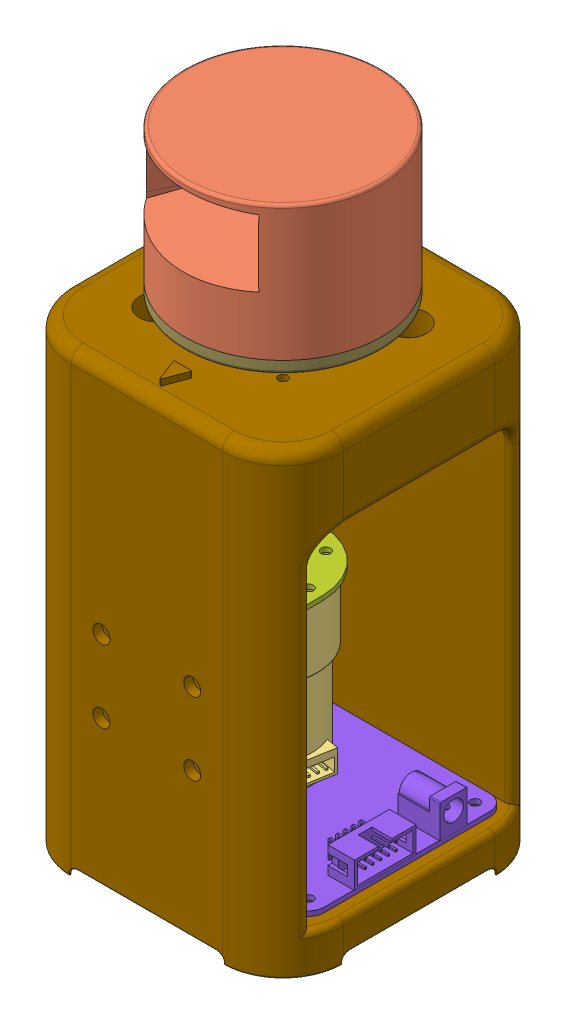
SolidWorks assembly 动画制作, configuration 默认. Lengths in mm.
Overall size (139.14 209.97 139.14).
12 component instances, 12 part files, 31 mates.
Components (placement in the parent):
- TFminiPlus激光测距模组-1: TFminiPlus激光测距模组 [默认] at (220.1693 461.3412 -162.2181) x (0.983804 0 0.179245) z (0 -1 0) size (35 21.2 40.5)
- 转子盖-1: 转子盖 [Default] at (216.4052 396.0912 -141.5582) x (-0.983804 0 -0.179245) z (0 1 0) size (65 68.94 49.1)
- MG513电机-光电编码器-1: MG513电机-光电编码器 [Default] at (216.4052 352.7568 -134.5582) x (1 0 0) z (0 0 -1) size (37.69 78.06 36.8)
- 传动轴-1: 传动轴 [Default] at (216.4052 354.2568 -141.5582) x (-0.541749 0 -0.840541) z (0.840541 0 -0.541749) size (8 80 8)
- 弹性联轴器-1: 弹性联轴器 [Default] at (216.4052 383.2568 -141.5582) x (-0.837169 0 -0.546944) z (-0.546944 0 0.837169) size (19 24.5 19)
- 导电滑环-1: 导电滑环 [Default] at (216.4052 396.0912 -141.5582) size (53 60.9 35)
- 电机支架-1: 电机支架 [Default] at (216.4052 333.5068 -108.5582) x (0 -1 0) z (1 0 0) size (41.5 46 40)
- 定子PCB-1: 定子PCB [Default] at (215.8366 283.2568 -144.1137) x (0.704694 0 0.709511) z (0 1 0) size (98.35 98.42 12.6)
- 定子底座-1: 定子底座 [Default] at (216.4052 396.0912 -141.5582) size (90.05 152.88 92.03)
- 红外接收管-1: 红外接收管 [Default] at (234.4268 410.0912 -123.5365) size (5.75 36.7 5.51)
- 转子PCB-1: 转子PCB [默认] at (216.4052 437.0912 -141.5582) x (-0.644225 0 -0.764836) z (0 1 0) size (54.26 53.21 16.1)
- 转子基座-2: 转子基座 [Default] at (216.4052 427.0912 -141.5582) x (-0.983804 0 -0.179245) z (0 1 0) size (65 65 43.53)
Mates (geometry in assembly coordinates):
- 同心6: concentric: cylinder of ? through (216.4052 421.0912 -141.5582) axis (0 -1 0) radius 17.5; cylinder of ? through (216.4052 421.0912 -141.5582) axis (0 -1 0) radius 17.75
- 同心7: concentric: cylinder of ? through (216.4052 421.0912 -141.5582) axis (0 -1 0) radius 17.5; cylinder of ? through (216.4052 421.0912 -141.5582) axis (0 -1 0) radius 17.75
- 重合10: coincident: plane of ? through (216.4052 421.0912 -141.5582) normal (0 1 0); plane of ? through (216.4052 421.0912 -141.5582) normal (0 1 0)
- 重合11: coincident: plane of ? through (216.4052 427.0912 -141.5582) normal (0 1 0); plane of ? through (216.4052 427.0912 -141.5582) normal (0 -1 0)
- 同心10: concentric: cylinder of ? through (216.4052 380.0912 -141.5582) axis (0 1 0) radius 4; cylinder of ? through (216.4052 450.0912 -141.5582) axis (0 -1 0) radius 4.05
- 重合12: coincident: plane of ? through (201.1758 461.3412 -127.099) normal (-0.725207 0 0.688531); plane of ? through (186.4246 516.3748 -142.636) normal (0.725207 0 -0.688531)
- 重合13: coincident: plane of ? through (221.9276 452.0912 -122.6703) normal (0 -1 0); plane of ? through (216.4052 452.0912 -141.5582) normal (0 1 0)
- 同心11: concentric: cylinder of ? through (194.4372 467.0912 -140.006) axis (-0.725207 0 0.688531) radius 1; cylinder of ? through (175.5819 467.0912 -122.1042) axis (0.725207 0 -0.688531) radius 1.1
- 同心12: concentric: cylinder of ? through (213.7161 455.5912 -119.7002) axis (-0.725207 0 0.688531) radius 1; cylinder of ? through (194.8607 455.5912 -101.7984) axis (0.725207 0 -0.688531) radius 1.1
- 同心13: concentric: cylinder of ? through (216.4052 475.5912 -141.5582) axis (0 -1 0) radius 32.5; cylinder of ? through (216.4052 431.0912 -141.5582) axis (0 -1 0) radius 32.5
- 同心14: concentric: cylinder of ? through (237.7988 455.5765 -161.8698) axis (0 -1 0) radius 3; cylinder of ? through (237.7988 421.1917 -161.8698) axis (0 1 0) radius 3.5
- 重合15: coincident: plane of ? through (216.4052 431.0912 -141.5582) normal (0 -1 0); plane of ? through (216.4052 431.0912 -141.5582) normal (0 1 0)
- 重合16: coincident: plane of ? through (75.2869 197.6495 -182.5073) normal (0 0 -1); plane of ? through (216.4052 437.0912 -141.5582) normal (0 1 0)
- 同心15: concentric: cylinder of ? through (75.2869 197.6495 -180.9073) axis (0 0 -1) radius 28.5; cylinder of ? through (216.4052 437.0912 -141.5582) axis (0 -1 0) radius 30
- 同心16: concentric: cylinder of ? through (56.4962 220.3906 -180.9073) axis (0 0 -1) radius 5; cylinder of ? through (237.7988 421.1917 -161.8698) axis (0 1 0) radius 3.5
- 重合17: coincident: plane of ? through (126.7477 256.0896 -289.8051) normal (0 -1 0); plane of ? through (171.4052 177.4603 -108.5582) normal (0 0 -1)
- 同心17: concentric: cylinder of ? through (115.4977 256.0896 -304.8051) axis (0 1 0) radius 1.75; cylinder of ? through (201.4052 344.7568 -114.5582) axis (0 0 1) radius 1.5
- 同心18: concentric: cylinder of ? through (115.4977 256.0896 -274.8051) axis (0 1 0) radius 1.75; cylinder of ? through (231.4052 344.7568 -114.5582) axis (0 0 1) radius 1.5
- 重合18: coincident: unknown of ?; unknown of ?
- 同心21: concentric: cylinder of ? through (216.4241 318.822 20.9428) axis (0 1 0) radius 6; cylinder of ? through (105.9977 289.0896 -289.8051) axis (1 0 0) radius 6.5
- 平行3: parallel: cylinder of ? through (105.9977 268.6662 -297.5551) axis (1 0 0) radius 1.6; cylinder of ? through (208.6741 330.822 0.5194) axis (0 -1 0) radius 1.5
- 重合19: coincident: unknown of ?; unknown of ?
- 同心24: concentric: cylinder of ? through (216.4241 305.022 20.9428) axis (0 1 0) radius 3; cylinder of ? through (281.4007 473.5052 -131.4361) axis (0 1 0) radius 4
- 同心25: concentric: cylinder of ? through (148.5562 240.0741 102.1235) axis (0 -1 0) radius 4; cylinder of ? through (216.4052 380.0912 -141.5582) axis (0 1 0) radius 4
- 重合20: coincident: plane of ? through (148.5562 160.0741 102.1235) normal (0 -1 0); plane of ? through (105.9977 257.5896 -269.8051) normal (-1 0 0)
- 重合21: coincident: plane of ? through (77.8041 4.3623 -289.9812) normal (0 0 -1); plane of ? through (216.4052 283.2568 -141.5582) normal (0 1 0)
- 同心26: concentric: cylinder of ? through (88.1096 92.7862 -289.9812) axis (0 0 1) radius 1.55; cylinder of ? through (251.4052 293.2568 -170.0582) axis (0 -1 0) radius 1.55
- 同心27: concentric: cylinder of ? through (77.8041 4.3623 -289.9812) axis (0 0 1) radius 1.55; cylinder of ? through (181.4052 293.2568 -115.0582) axis (0 -1 0) radius 1.55
- 同心28: concentric: cylinder of ? through (234.4268 419.0912 -123.5365) axis (0 -1 0) radius 2.5; cylinder of ? through (64.1162 4.0765 -284.7924) axis (0 -1 0) radius 2.46
- 重合22: coincident: plane of ? through (216.4052 411.0912 -141.5582) normal (0 -1 0); plane of ? through (64.1162 -3.5235 -284.7924) normal (0 1 0)
- 同心31: concentric: cylinder of ? through (231.9241 330.822 13.9428) axis (0 -1 0) radius 1.5; cylinder of ? through (105.9977 282.0896 -274.3051) axis (1 0 0) radius 1.6
